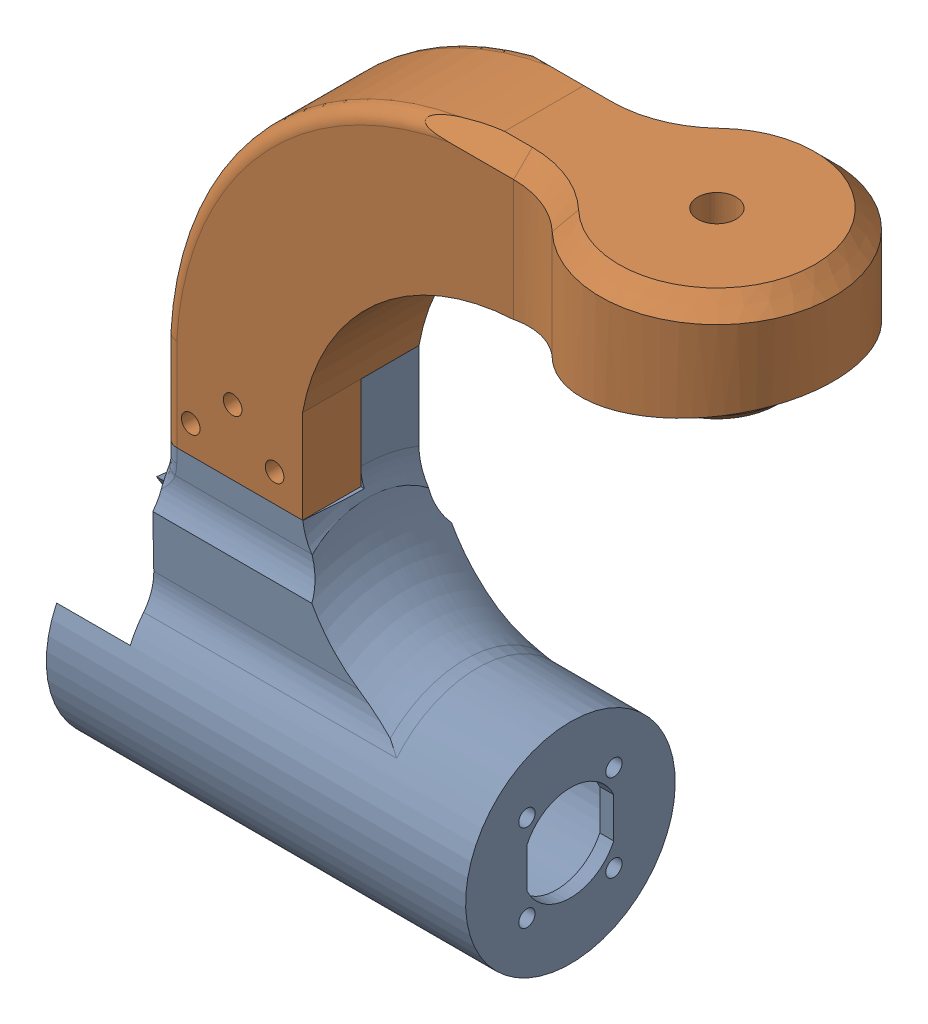
SolidWorks assembly Wheel_Steer_Assemblyleftleft1, configuration Default. Lengths in mm.
Overall size (146.44 156.21 50).
2 component instances, 2 part files, 6 mates.
Components (placement in the parent):
- Motor_holder_end_wheelsleft1-1: Motor_holder_end_wheelsleft1 [Default] at (-15 -43.7083 -12.5) x (0 1 0) z (-1 0 0) size (86.21 45 90)
- Steer_to_motor_holderleft1-1: Steer_to_motor_holderleft1 [Default] at origin size (131.61 90 50)
Mates (geometry in assembly coordinates):
- Coincident1: coincident aligned: plane of Steer_to_motor_holderleft1-1 through (0 0 0) normal (0 0 1)
- Coincident2: coincident aligned: plane of Steer_to_motor_holderleft1-1 through (0 0 0) normal (0 1 0)
- Coincident3: coincident aligned: plane of Steer_to_motor_holderleft1-1 through (0 0 0) normal (1 0 0)
- Coincident4: coincident anti-aligned: plane of Motor_holder_end_wheelsleft1-1 through (48 20 -12.5) normal (0 0 1); plane of Steer_to_motor_holderleft1-1 through (49 0 -12.5) normal (0 0 -1)
- Coincident5: coincident anti-aligned: plane of Motor_holder_end_wheelsleft1-1 through (48 20 -25) normal (0 1 0); plane of Steer_to_motor_holderleft1-1 through (49 20 -12.5) normal (0 -1 0)
- Coincident6: coincident aligned: plane of Motor_holder_end_wheelsleft1-1 through (30 -10 0) normal (1 0 0); plane of Steer_to_motor_holderleft1-1 through (30 0 -25) normal (1 0 0)
